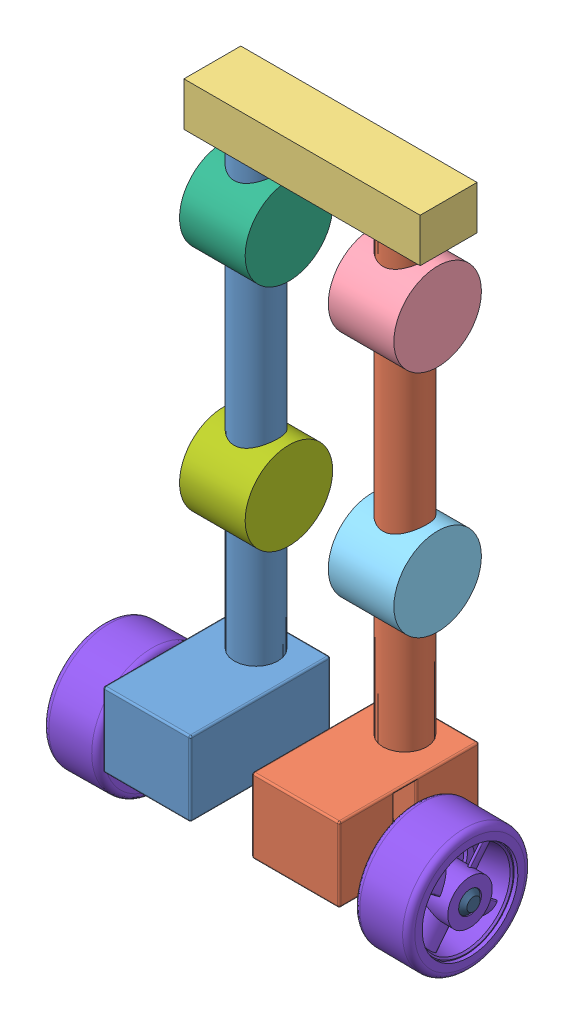
SolidWorks assembly Assem1, configuration Default. Lengths in mm.
Overall size (428.14 732.61 198.07).
49 component instances, 16 part files, 17 mates.
Components (placement in the parent):
- foot 1-1: foot 1 [Default] at (63.8048 0.6497 487.5783) size (100 590 160)
- foot 2-1: foot 2 [Default] at (233.8048 0.6497 487.5783) size (100 590 160)
- weist-1: weist [Default] at (153.8052 590.6497 491.9278) size (270 50 65)
- 1 (1)-1: 1 (1) [Default] at (186.2952 517.8949 504.0203) size (75 100 100)
- 1 (2)-1: 1 (2) [Default] at (186.2952 255.7611 504.0203) size (75 100 100)
- 1 (3)-1: 1 (3) [Default] at (16.2952 517.8949 504.0203) size (75 100 100)
- 1 (4)-1: 1 (4) [Default] at (16.2952 255.7611 504.0203) size (75 100 100)
- final-2: final [Default] at (-70.139 6.2617 553.916) x (0.999933 0.011569 0) z (0 0 1) size (148.74 196.36 196.36)
  - part5-1: part5 [Default] x (0 -0.791913 -0.610634) z (1 0 0) size (140 140 63)
  - Part7-1: Part7 [Default] at (63 0 0) x (0 -0.533886 -0.845556) z (1 0 0) size (85 85 10)
  - part6-1: part6 [Default] at (16 0 0) size (94 41.69 29.99)
  - Part8-1: Part8 [Default] at (87.5 25 -10.5) x (-0.723993 -0.689807 0) z (0 0 1) size (6 6 16)
  - Part2-1: Part2 [Default] at (92.9524 31.5696 0) x (0 0 1) z (0.769505 -0.638641 0) size (10.3 28.5 10.3)
  - Part3-1: Part3 [Default] at (107.1194 -5.67 0) x (-0.995728 -0.092332 0) z (0.092332 -0.995728 0) size (37.5 5 5)
  - Part3-2: Part3 [Default] at (107.4354 7.5 0) x (-1 0 0) z (0 -1 0) size (37.5 5 5)
  - Part8-2: Part8 [Default] at (87.5 5 -10.5) x (-0.96854 0.248858 0) z (0 0 1) size (6 6 16)
  - Part8-3: Part8 [Default] at (87.5 -10 -10.5) x (-0.152895 0.988242 0) z (0 0 1) size (6 6 16)
  - Part4-1: Part4 [Default] at (132.9059 27.3137 -0.25) x (0.011569 0.999933 0) z (0 0 1) size (80 28 22.45)
  - Part8-4: Part8 [Default] at (120 5 -8.75) x (-0.910491 -0.413528 0) z (0 0 1) size (6 6 16)
  - Part8-5: Part8 [Default] at (119.8612 -6.9992 -8.75) x (-0.549173 -0.835709 0) z (0 0 1) size (6 6 16)
  - Part1-1: Part1 [Default] at (118.1396 61.918 0) x (0.769505 -0.638641 0) z (0 0 1) size (11 29 11)
  - Part8-6: Part8 [Default] at (120.6942 64.996 -8.75) x (-0.100518 0.994935 0) z (0 0 1) size (6 6 16)
  - Part9-1: Part9 [Default] at (87.5 -10 -6) size (5.2 4.5 3.5)
  - Part9-2: Part9 [Default] at (87.5 5 -6) size (5.2 4.5 3.5)
  - Part9-3: Part9 [Default] at (120.6942 64.996 -8.25) size (5.2 4.5 3.5)
  - Part9-4: Part9 [Default] at (120 5 -8.25) size (5.2 4.5 3.5)
  - Part9-5: Part9 [Default] at (87.5 25 -6) size (5.2 4.5 3.5)
  - Part9-6: Part9 [Default] at (119.8612 -6.9992 -8.25) size (5.2 4.5 3.5)
- final-4: final [Default] at (347.7293 6.2617 553.4696) x (-0.999933 0.011569 0) z (0 0 -1) size (148.74 196.36 196.36)
  - part5-1: part5 [Default] x (0 -0.791913 -0.610634) z (1 0 0) size (140 140 63)
  - Part7-1: Part7 [Default] at (63 0 0) x (0 -0.533886 -0.845556) z (1 0 0) size (85 85 10)
  - part6-1: part6 [Default] at (16 0 0) size (94 41.69 29.99)
  - Part8-1: Part8 [Default] at (87.5 25 -10.5) x (-0.723993 -0.689807 0) z (0 0 1) size (6 6 16)
  - Part2-1: Part2 [Default] at (92.9524 31.5696 0) x (0 0 1) z (0.769505 -0.638641 0) size (10.3 28.5 10.3)
  - Part3-1: Part3 [Default] at (107.1194 -5.67 0) x (-0.995728 -0.092332 0) z (0.092332 -0.995728 0) size (37.5 5 5)
  - Part3-2: Part3 [Default] at (107.4354 7.5 0) x (-1 0 0) z (0 -1 0) size (37.5 5 5)
  - Part8-2: Part8 [Default] at (87.5 5 -10.5) x (-0.96854 0.248858 0) z (0 0 1) size (6 6 16)
  - Part8-3: Part8 [Default] at (87.5 -10 -10.5) x (-0.152895 0.988242 0) z (0 0 1) size (6 6 16)
  - Part4-1: Part4 [Default] at (132.9059 27.3137 -0.25) x (0.011569 0.999933 0) z (0 0 1) size (80 28 22.45)
  - Part8-4: Part8 [Default] at (120 5 -8.75) x (-0.910491 -0.413528 0) z (0 0 1) size (6 6 16)
  - Part8-5: Part8 [Default] at (119.8612 -6.9992 -8.75) x (-0.549173 -0.835709 0) z (0 0 1) size (6 6 16)
  - Part1-1: Part1 [Default] at (118.1396 61.918 0) x (0.769505 -0.638641 0) z (0 0 1) size (11 29 11)
  - Part8-6: Part8 [Default] at (120.6942 64.996 -8.75) x (-0.100518 0.994935 0) z (0 0 1) size (6 6 16)
  - Part9-1: Part9 [Default] at (87.5 -10 -6) size (5.2 4.5 3.5)
  - Part9-2: Part9 [Default] at (87.5 5 -6) size (5.2 4.5 3.5)
  - Part9-3: Part9 [Default] at (120.6942 64.996 -8.25) size (5.2 4.5 3.5)
  - Part9-4: Part9 [Default] at (120 5 -8.25) size (5.2 4.5 3.5)
  - Part9-5: Part9 [Default] at (87.5 25 -6) size (5.2 4.5 3.5)
  - Part9-6: Part9 [Default] at (119.8612 -6.9992 -8.25) size (5.2 4.5 3.5)
Mates (geometry in assembly coordinates):
- Coincident1: coincident aligned: circle of foot 1-1; circle of weist-1
- Coincident2: coincident aligned: circle of foot 2-1; circle of weist-1
- Concentric6: concentric aligned: cylinder of foot 2-1 through (223.7952 590.6497 504.0203) axis (0 -1 0) radius 25; cylinder of 1 (1)-1 through (223.7952 617.8949 504.0203) axis (0 -1 0) radius 25
- Concentric7: concentric aligned: cylinder of foot 2-1 through (223.7952 590.6497 504.0203) axis (0 -1 0) radius 25; cylinder of 1 (2)-1 through (223.7952 355.7611 504.0203) axis (0 -1 0) radius 25
- Concentric8: concentric aligned: cylinder of foot 1-1 through (53.7952 590.6497 504.0203) axis (0 -1 0) radius 25; cylinder of 1 (3)-1 through (53.7952 617.8949 504.0203) axis (0 -1 0) radius 25
- Concentric9: concentric aligned: cylinder of foot 1-1 through (53.7952 590.6497 504.0203) axis (0 -1 0) radius 25; cylinder of 1 (4)-1 through (53.7952 355.7611 504.0203) axis (0 -1 0) radius 25
- Parallel6: parallel anti-aligned: plane of 1 (2)-1 through (186.2952 255.7611 504.0203) normal (-1 0 0); plane of 1 (4)-1 through (91.2952 255.7611 504.0203) normal (1 0 0)
- Parallel7: parallel anti-aligned: plane of 1 (1)-1 through (186.2952 517.8949 504.0203) normal (-1 0 0); plane of 1 (3)-1 through (91.2952 517.8949 504.0203) normal (1 0 0)
- Parallel8: parallel anti-aligned: plane of foot 1-1 through (103.7952 85.6497 469.0203) normal (1 0 0); plane of foot 2-1 through (173.7952 85.6497 469.0203) normal (-1 0 0)
- Parallel11: parallel aligned: plane of foot 2-1 through (273.7952 85.6497 469.0203) normal (1 0 0); plane of weist-1 through (273.7952 640.6497 471.5203) normal (1 0 0)
- Parallel12: parallel aligned: plane of foot 1-1 through (3.7952 85.6497 469.0203) normal (-1 0 0); plane of weist-1 through (3.7952 640.6497 471.5203) normal (-1 0 0)
- Concentric10: concentric aligned: cylinder of 1 (2)-1 through (261.2952 255.7611 504.0203) axis (-1 0 0) radius 50; cylinder of 1 (4)-1 through (91.2952 255.7611 504.0203) axis (-1 0 0) radius 50
- Concentric11: concentric aligned: cylinder of 1 (1)-1 through (261.2952 517.8949 504.0203) axis (-1 0 0) radius 50; cylinder of 1 (3)-1 through (91.2952 517.8949 504.0203) axis (-1 0 0) radius 50
- Coincident9: coincident anti-aligned: line of foot 1-1 through (73.7952 0.6497 541.2564) axis (0 0 1); line of final-2/Part4-1 through (73.7952 0.6497 564.866) axis (0 0 -1)
- Coincident13: coincident anti-aligned: plane of foot 1-1 through (73.7952 0.6497 487.5783) normal (-1 0 0); plane of final-2/Part4-1 through (73.7952 35.1112 564.866) normal (1 0 0)
- Coincident15: coincident anti-aligned: plane of foot 2-1 through (203.7952 0.6497 487.5783) normal (1 0 0); plane of final-4/Part4-1 through (203.7952 35.1112 542.5196) normal (-1 0 0)
- Coincident16: coincident anti-aligned: line of foot 2-1 through (203.7952 0.6497 566.2564) axis (0 0 -1); line of final-4/Part4-1 through (203.7952 0.6497 542.5196) axis (0 0 1)
